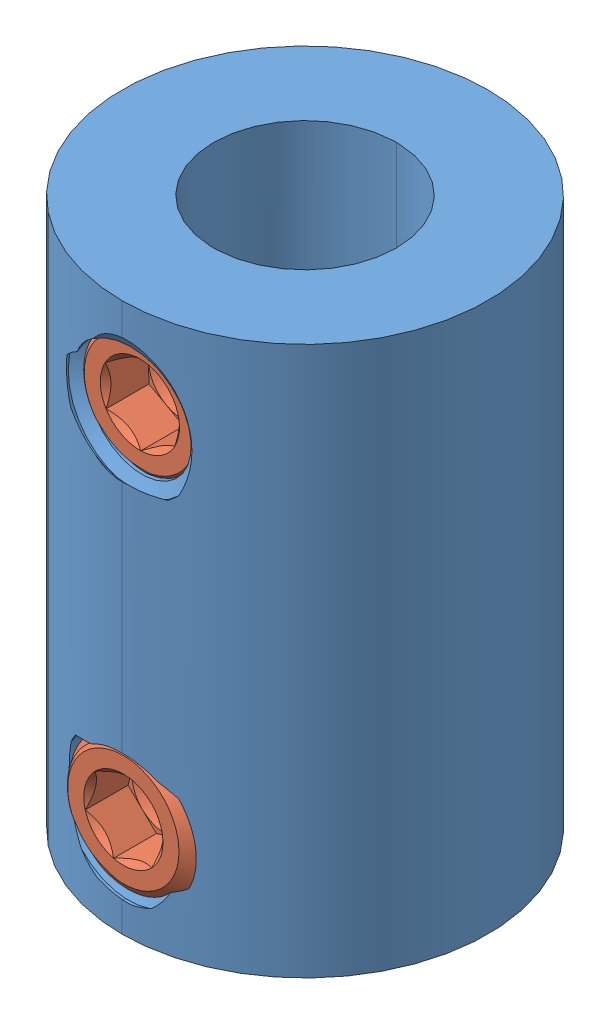
SolidWorks assembly 625182 assembly, configuration Default. Lengths in mm.
Overall size (12.69 19.05 12.7).
3 component instances, 2 part files, 0 mates.
Components (placement in the parent):
- 625182.STEP-1: 625182.STEP [Default] at (-82.5901 10.1505 30.1389) size (12.69 19.05 12.7)
- 632134_91375A436.STEP-1: 632134_91375A436.STEP [Default] at (-82.5901 13.5795 35.2544) x (0.968797 -0.247855 0) z (0 0 1) size (4.83 4.83 3.18)
- 632134_91375A436.STEP-2: 632134_91375A436.STEP [Default] at (-82.5901 25.7715 34.6806) x (0.999731 0.023194 0) z (0 0 1) size (4.83 4.83 3.18)
